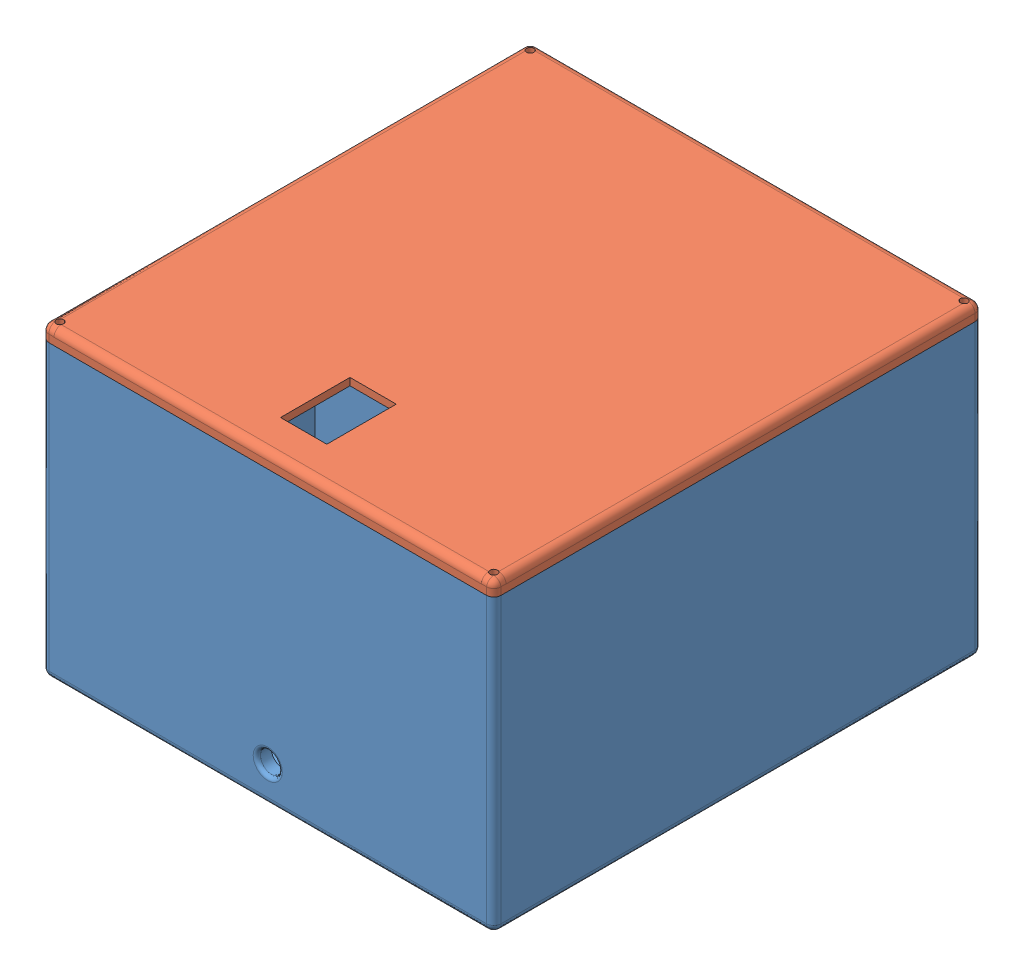
SolidWorks assembly Analog Computer Power Supply, configuration Default. Lengths in mm.
Overall size (124 84 134).
2 component instances, 2 part files, 2 mates.
Components (placement in the parent):
- bottom-powersupply-1: bottom-powersupply [Default] at (54.7278 11.6849 112.0865) size (124 82 134)
- top-powersupply-1: top-powersupply [Default] at (54.7278 95.6849 112.0865) x (-1 0 0) z (0 0 1) size (124 4 134)
Mates (geometry in assembly coordinates):
- Coincident1: coincident: circle of bottom-powersupply-1; circle of top-powersupply-1
- Coincident2: coincident anti-aligned: circle of bottom-powersupply-1; circle of top-powersupply-1
